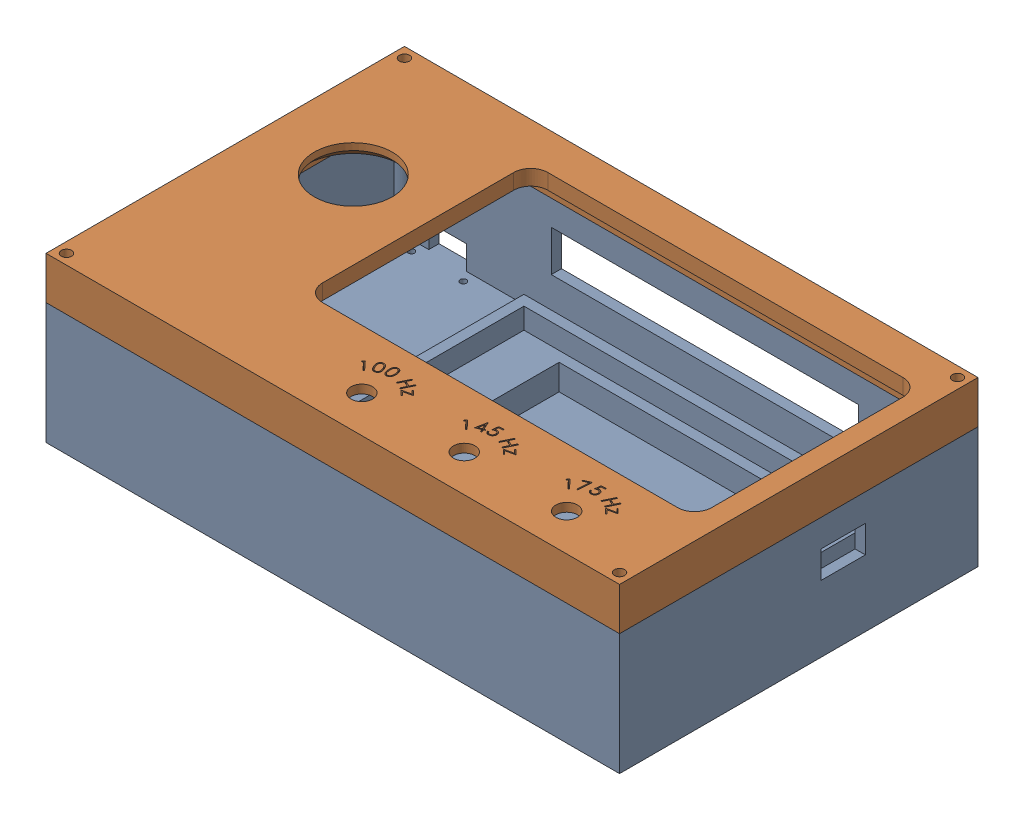
SolidWorks assembly BT Controller Assembly Intern 2024, configuration Default. Lengths in mm.
Overall size (168 48 105).
2 component instances, 2 part files, 6 mates.
Components (placement in the parent):
- Arduino BT Controller Intern 2024-1: Arduino BT Controller Intern 2024 [Default] at origin size (168 35.5 105)
- Arduino BT Controller Lid Intern 2024-1: Arduino BT Controller Lid Intern 2024 [Default] at (168 35.5 0) size (168 12.5 105)
Mates (geometry in assembly coordinates):
- Coincident1: coincident anti-aligned: plane of Arduino BT Controller Intern 2024-1 through (0 0 0) normal (0 -1 0)
- Coincident2: coincident aligned: plane of Arduino BT Controller Intern 2024-1 through (0 35.5 0) normal (0 0 1)
- Coincident3: coincident anti-aligned: plane of Arduino BT Controller Intern 2024-1 through (0 35.5 0) normal (-1 0 0)
- Concentric1: concentric anti-aligned: cylinder of Arduino BT Controller Intern 2024-1 through (165 -4.2426 -102) axis (0 1 0) radius 1.5; cylinder of Arduino BT Controller Lid Intern 2024-1 through (165 48 -102) axis (0 -1 0) radius 1.5
- Concentric2: concentric anti-aligned: cylinder of Arduino BT Controller Intern 2024-1 through (165 -4.2426 -3) axis (0 1 0) radius 1.5; cylinder of Arduino BT Controller Lid Intern 2024-1 through (165 48 -3) axis (0 -1 0) radius 1.5
- Coincident4: coincident anti-aligned: plane of Arduino BT Controller Intern 2024-1 through (0 35.5 0) normal (0 1 0); plane of Arduino BT Controller Lid Intern 2024-1 through (168 35.5 0) normal (0 -1 0)
